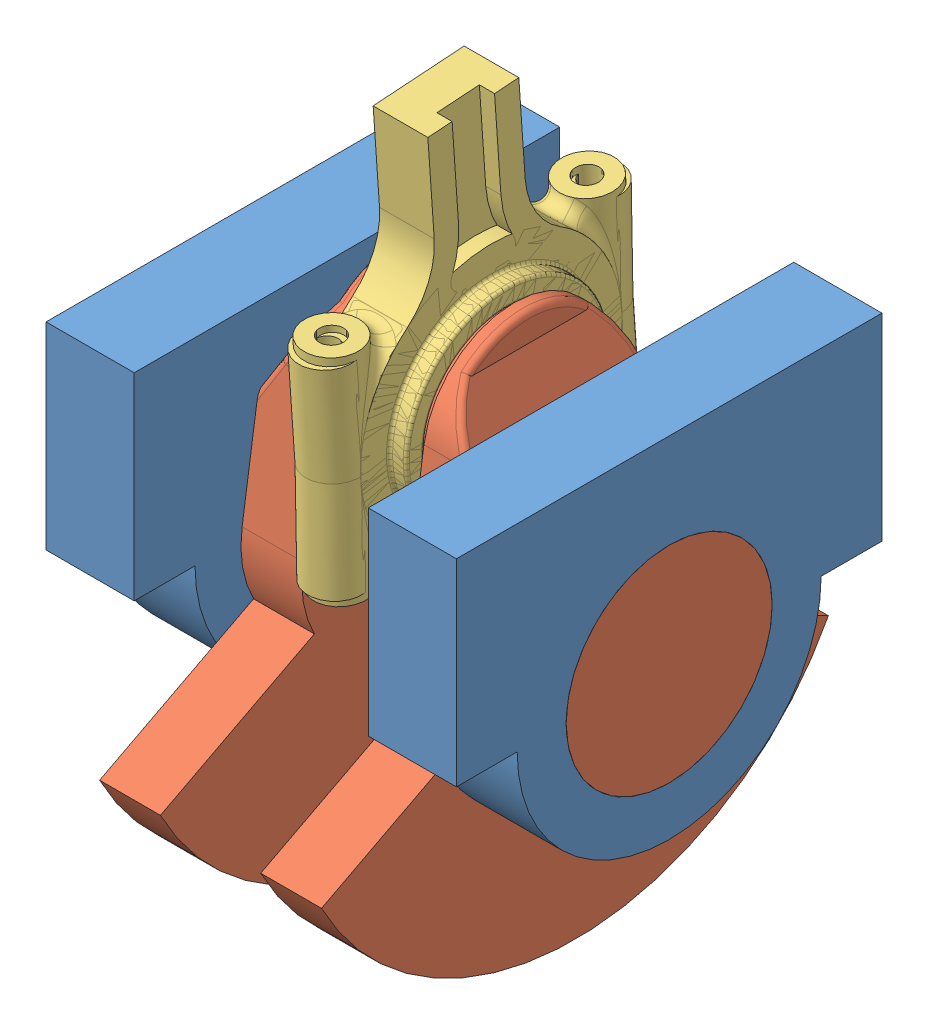
SolidWorks assembly Сборка, configuration По умолчанию. Lengths in mm.
Overall size (135 229.92 166.76).
5 component instances, 3 part files, 14 mates.
Components (placement in the parent):
- держалка-1: держалка [По умолчанию] at (29 0 0) x (0 0 1) z (-1 0 0) size (140 115 29)
- держалка-2: держалка [По умолчанию] at (135 0 0) x (0 0 1) z (-1 0 0) size (140 115 29)
- колено вала-2: колено вала [По умолчанию] at origin size (135 171.5 166.76)
- половина верха шатуна-4: половина верха шатуна [По умолчанию] at (67.5 206.1127 11.0913) x (1 0 0) z (0 -0.069756 0.997564) size (29 128 104)
- половина верха шатуна-5: половина верха шатуна [По умолчанию] at (67.5 -111.4758 -2.7749) x (1 0 0) z (0 0.017452 -0.999848) size (29 128 104)
Mates (geometry in assembly coordinates):
- Совпадение9: coincident aligned: plane of держалка-2 through (135 0 0) normal (1 0 0); plane of колено вала-2 through (135 0 0) normal (1 0 0)
- Совпадение10: coincident anti-aligned: circle of держалка-2; circle of колено вала-2
- Концентричный7: concentric anti-aligned: cylinder of держалка-1 through (0 0 0) axis (1 0 0) radius 33.9; cylinder of колено вала-2 through (31 0 0) axis (-1 0 0) radius 33.9
- Совпадение13: coincident aligned: plane of держалка-1 through (0 0 0) normal (-1 0 0); plane of колено вала-2 through (0 0 0) normal (-1 0 0)
- Параллельность2: parallel aligned: plane of держалка-1 through (0 65 0) normal (0 1 0); plane of держалка-2 through (106 65 0) normal (0 1 0)
- Параллельность3: parallel anti-aligned: plane of держалка-1 through (0 0 -70) normal (0 0 -1); plane of колено вала-2 through (0 0 0) normal (0 0 1)
- Угол11: planar angle = 3.071779 rad anti-aligned: plane of половина верха шатуна-4 through (67.5 132.2929 5.9293) normal (0 0.997564 0.069756); plane of держалка-1 through (0 65 0) normal (0 1 0)
- Угол2: planar angle = 6.265732 rad anti-aligned: plane of половина верха шатуна-5 through (67.5 -37.4871 -1.4835) normal (0 -0.999848 -0.017452); plane of держалка-1 through (0 65 0) normal (0 1 0)
- Совпадение19: coincident aligned: plane of половина верха шатуна-4 through (67.5 206.1127 11.0913) normal (1 0 0); plane of половина верха шатуна-5 through (67.5 -111.4758 -2.7749) normal (1 0 0)
- Совпадение20: coincident aligned: circle of половина верха шатуна-4; circle of половина верха шатуна-5
- Совпадение21: coincident: line of колено вала-2 through (188.65 67.5 -102.575) axis (0 0 1); plane of половина верха шатуна-5 through (67.5 -111.4758 -2.7749) normal (1 0 0)
- Концентричный8: concentric anti-aligned: cylinder of колено вала-2 through (67.5 47.5 0) axis (-1 0 0) radius 27; cylinder of половина верха шатуна-5 through (58.5 47.5 0) axis (1 0 0) radius 27.5
- Совпадение25: coordinate: point of колено вала-2
- Параллельность4: parallel aligned: plane of держалка-2 through (106 0 70) normal (0 0 1); plane of колено вала-2 through (0 0 0) normal (0 0 1)
